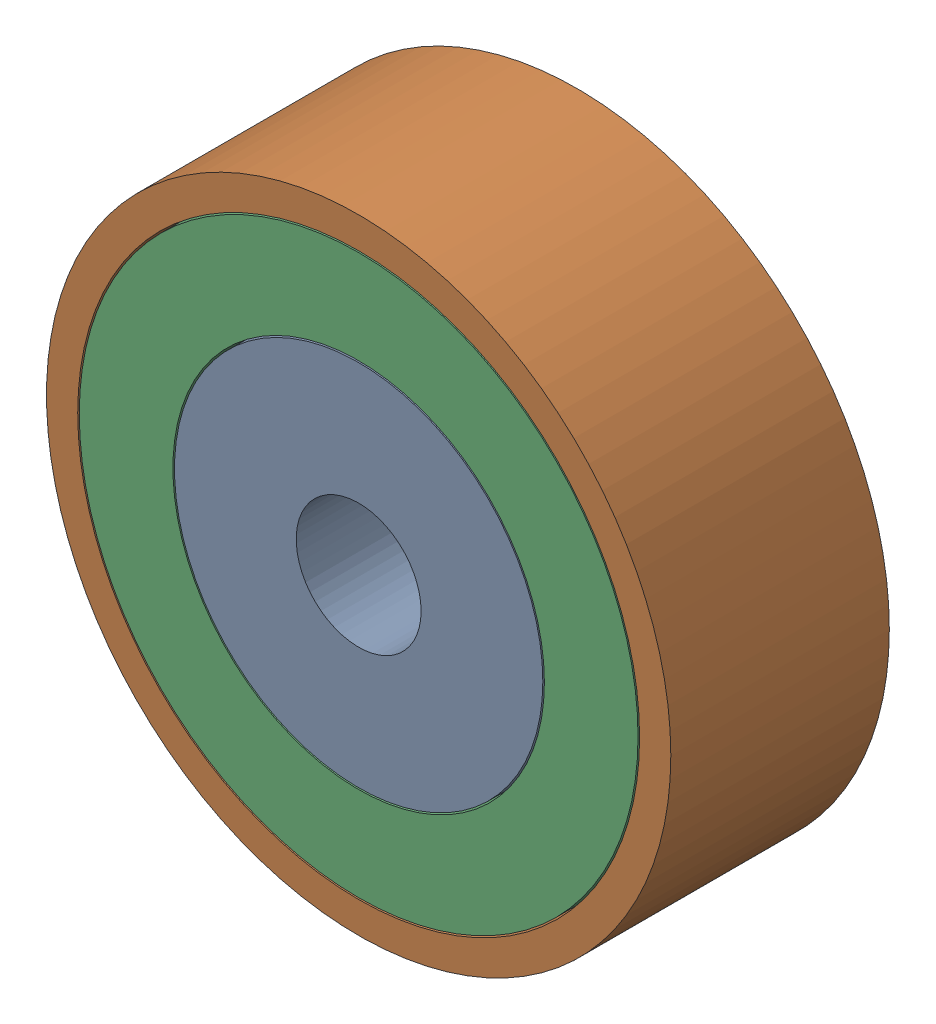
SolidWorks assembly 镜向轴承15, configuration 默认. Lengths in mm.
Overall size (20 20 7).
3 component instances, 3 part files, 4 mates.
Components (placement in the parent):
- 镜向轴承内圈-1: 镜向轴承内圈 [默认] at (-5.0655 0.8032 -6.5) size (11.8 11.8 7)
- 镜向轴承外圈-1: 镜向轴承外圈 [默认] at (-5.0655 0.8032 -6.5) size (20 20 7)
- 镜向轴承中圈-1: 镜向轴承中圈 [默认] at (-5.0655 0.8032 -6.5) size (17.9 17.9 7)
Mates (geometry in assembly coordinates):
- 重合1: coincident: plane of ? through (-5.0655 0.8032 -13.5) normal (0 0 -1); plane of ? through (-5.0655 0.8032 -13.5) normal (0 0 -1)
- 重合2: coincident: plane of ? through (-5.0655 0.8032 -13.5) normal (0 0 -1); plane of ? through (-5.0655 0.8032 -13.5) normal (0 0 -1)
- 同心1: concentric: cylinder of ? through (-5.0655 0.8032 -13.5) axis (0 0 1) radius 9; cylinder of ? through (-5.0655 0.8032 -13.5) axis (0 0 1) radius 8.95
- 同心2: concentric: cylinder of ? through (-5.0655 0.8032 -13.5) axis (0 0 1) radius 5.9; cylinder of ? through (-5.0655 0.8032 -13.5) axis (0 0 1) radius 5.95
